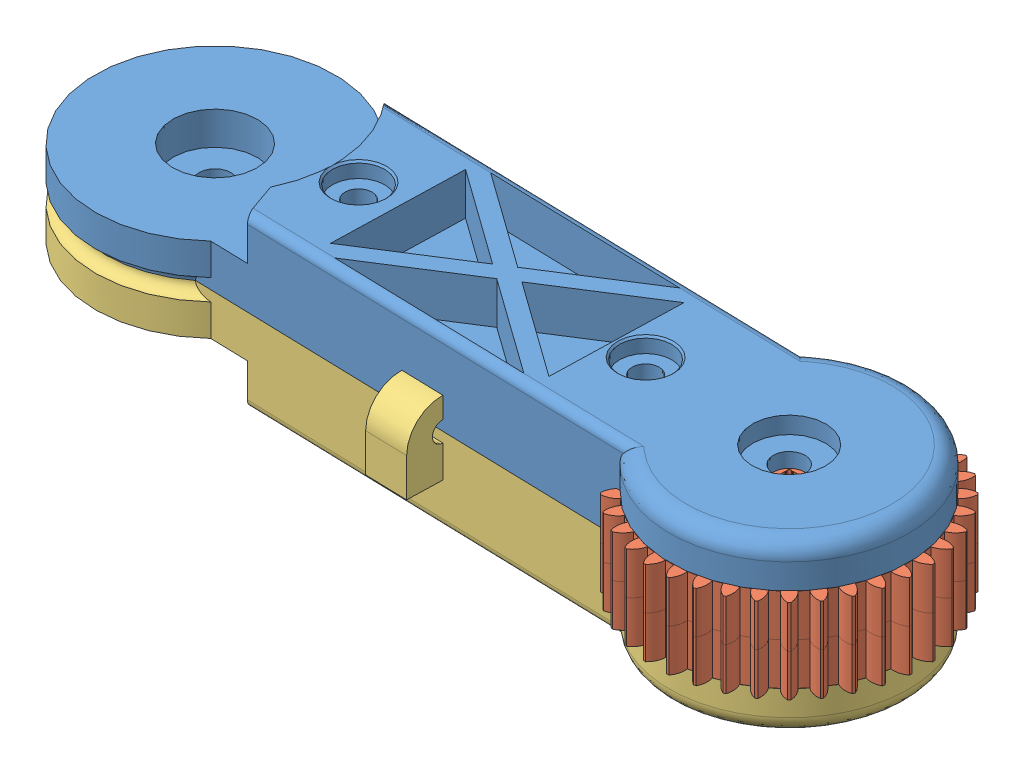
SolidWorks assembly HalfDogBoneAssemblyt, configuration Default. Lengths in mm.
Overall size (127.44 25.53 41.09).
4 component instances, 3 part files, 2 mates.
Components (placement in the parent):
- HalfDogBone-1: HalfDogBone [Default] at (58.483 65.7791 105.0954) x (0.999628 0 0.027267) z (-0.027267 0 0.999628) size (124.94 12.97 36.24)
- 36tooth gear-3: 36tooth gear [Default] at (67.4563 68.9541 103.6194) x (0 0 1) z (0 1 0) size (40.08 40.08 9.53)
- MirrorHalfDogBone-2: MirrorHalfDogBone [Default] at (58.483 65.7791 105.0954) x (0.999628 0 0.027267) z (0.027267 0 -0.999628) size (124.94 17.47 36.24)
- 36tooth gear-4: 36tooth gear [Default] at (67.4563 62.6041 103.6194) x (0 0 1) z (0 1 0) size (40.08 40.08 9.53)
Mates (geometry in assembly coordinates):
- Coincident6: coincident: plane of HalfDogBone-1 through (67.4563 65.7791 103.6194) normal (0 -1 0); plane of 36tooth gear-3 through (67.4563 65.7791 103.6194) normal (0 -1 0)
- Concentric1: concentric: circle of HalfDogBone-1; circle of 36tooth gear-3
